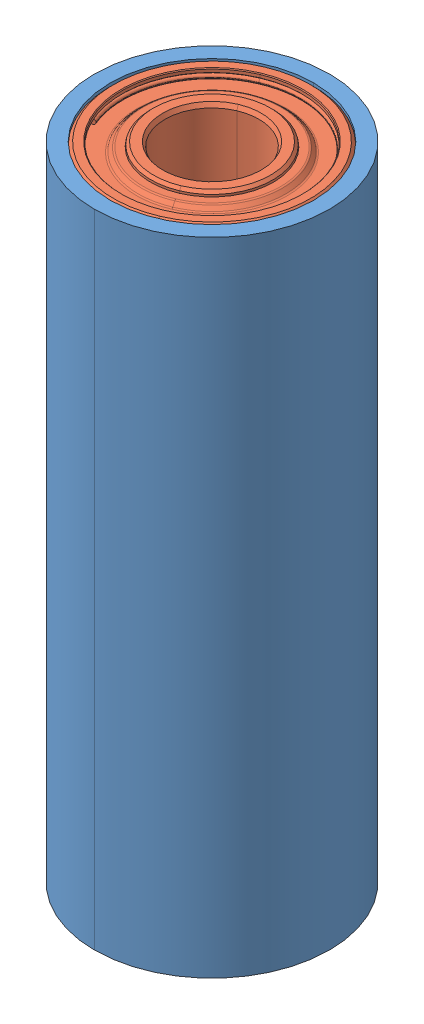
SolidWorks assembly 6mm ID idler pulley (1607-0041-0615), configuration Default. Lengths in mm.
Overall size (17.04 41 17.04).
4 component instances, 2 part files, 0 mates.
Components (placement in the parent):
- 1607-0041-0615 assembly.STEP-1: 1607-0041-0615 assembly.STEP [Default] at origin size (17.04 41 17.04)
  - 1607-0041-0615.STEP-1: 1607-0041-0615.STEP [Default] at (-22.1413 9.5426 5.2006) size (15 41 15)
  - 1600-0513-0006.STEP-1: 1600-0513-0006.STEP [Default] at (-22.1413 25.0426 5.2006) x (0.920811 0 -0.39001) z (0.39001 0 0.920811) size (13 5 13)
  - 1600-0513-0006.STEP-2: 1600-0513-0006.STEP [Default] at (-22.1413 -10.9574 5.2006) x (0.948511 0 0.316745) z (-0.316745 0 0.948511) size (13 5 13)
